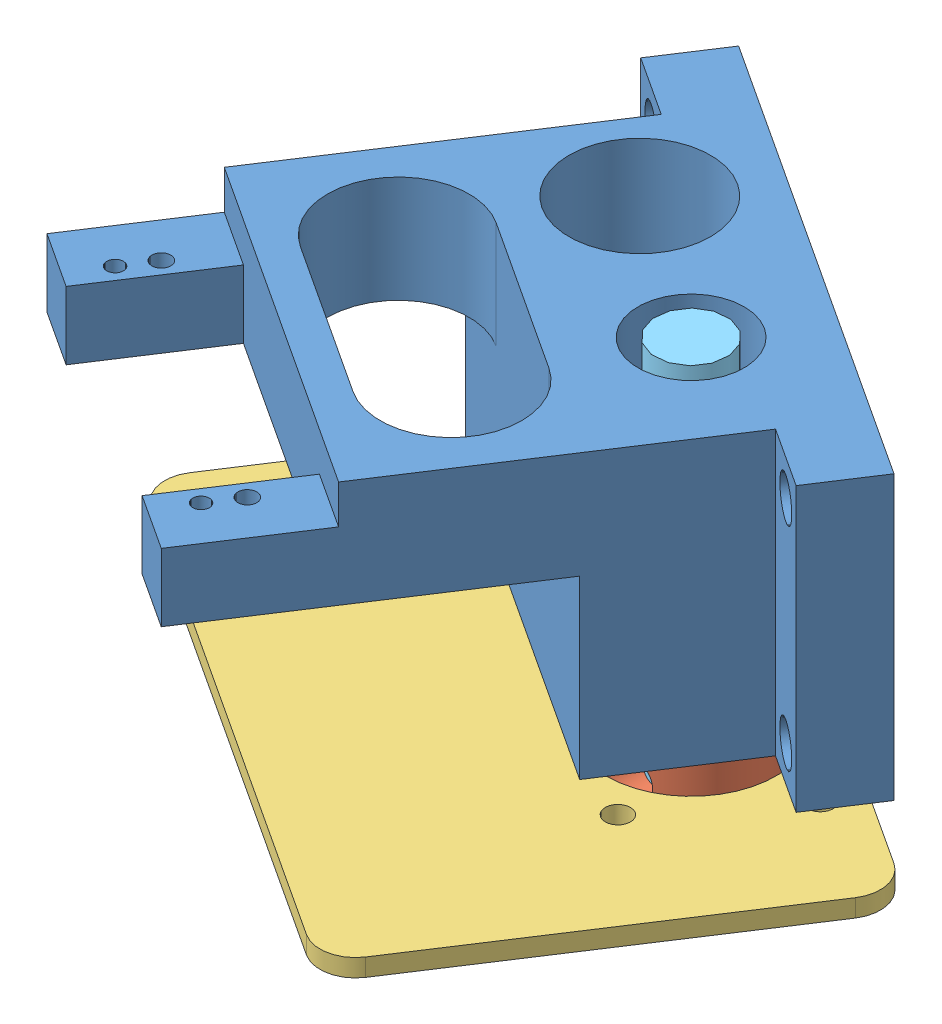
SolidWorks assembly Jet vane unit b, configuration Default. Lengths in mm.
Overall size (68.15 45.75 66.68).
5 component instances, 5 part files, 9 mates.
Components (placement in the parent):
- block_z-1: block_z [默认] at (87.8634 97.8667 18.8536) x (-0.837169 0 -0.546944) z (0.546944 0 -0.837169) size (48.05 25.4 46.19)
- collar_z-1: collar_z [默认] at (87.8634 92.3104 18.8536) size (12.7 7.94 12.7)
- heat_shiled-1: heat_shiled [默认] at (87.8634 96.1449 18.8536) x (-0.837169 0 -0.546944) z (0.546944 0 -0.837169) size (54.4 1.59 38.1)
- Bearing, flanged sleeve, 1_4in shaft_z-2: Bearing, flanged sleeve, 1_4in shaft_z [默认] at (87.8634 96.2792 18.8536) x (-0.837169 0 -0.546944) z (0 1 0) size (12.7 12.7 6.35)
- vane_shaft_b-1: vane_shaft_b [Default] at (87.8634 134.6967 18.8536) x (-0.837169 0 -0.546944) z (-0.546944 0 0.837169) size (6.35 45.75 6.35)
Mates (geometry in assembly coordinates):
- 重合10: coincident anti-aligned: plane of collar_z-1 through (87.8634 96.2792 18.8536) normal (0 1 0); plane of Bearing, flanged sleeve, 1_4in shaft_z-2 through (85.1948 96.2792 17.1101) normal (0 -1 0)
- 同心14: concentric anti-aligned: cylinder of collar_z-1 through (87.8634 88.3417 18.8536) axis (0 1 0) radius 6.35; cylinder of heat_shiled-1 through (87.8634 92.9699 18.8536) axis (0 -1 0) radius 7.62
- 同心15: concentric aligned: cylinder of block_z-1 through (65.9815 97.8667 12.3517) axis (0 -1 0) radius 0.889; cylinder of heat_shiled-1 through (65.9815 92.9699 12.3517) axis (0 -1 0) radius 1.1303
- 同心16: concentric aligned: cylinder of block_z-1 through (91.3896 97.8667 28.9515) axis (0 -1 0) radius 0.889; cylinder of heat_shiled-1 through (91.3896 92.9699 28.9515) axis (0 -1 0) radius 1.1303
- 重合15: coincident anti-aligned: plane of block_z-1 through (87.8634 97.8667 18.8536) normal (0 -1 0); plane of Bearing, flanged sleeve, 1_4in shaft_z-2 through (82.5474 97.8667 15.3805) normal (0 1 0)
- 同心17: concentric anti-aligned: cylinder of collar_z-1 through (87.8634 88.3417 18.8536) axis (0 -1 0) radius 3.175; cylinder of vane_shaft_b-1 through (87.8634 77.5467 18.8536) axis (0 1 0) radius 3.175
- 同心18: concentric anti-aligned: cylinder of Bearing, flanged sleeve, 1_4in shaft_z-2 through (87.8634 102.6292 18.8536) axis (0 -1 0) radius 3.1877; cylinder of vane_shaft_b-1 through (87.8634 77.5467 18.8536) axis (0 1 0) radius 3.175
- 重合16: coincident aligned: plane of collar_z-1 through (94.2134 88.3417 18.8536) normal (0 -1 0); plane of vane_shaft_b-1 through (87.8634 88.3417 18.8536) normal (0 -1 0)
- 平行1: parallel aligned: plane of heat_shiled-1 through (108.4985 92.9699 24.7499) normal (0.837169 0 0.546944); plane of vane_shaft_b-1 through (88.9353 88.3417 15.7613) normal (0.837169 0 0.546944)
